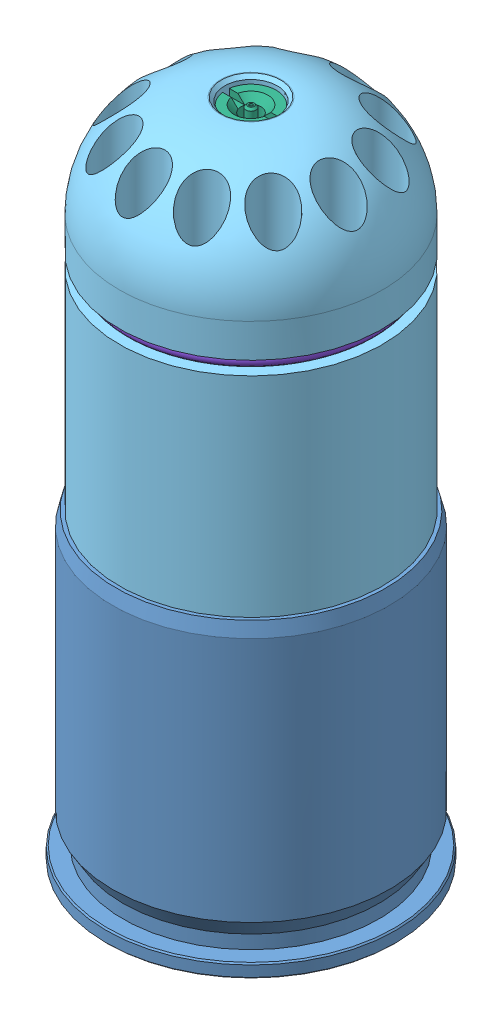
SolidWorks assembly 40mm-Klein, configuration Standard. Lengths in mm.
Overall size (51.21 98 51.21).
11 component instances, 8 part files, 20 mates.
Components (placement in the parent):
- Boden-G-1: Boden-G [Standard] at (-10.8436 -22.8172 45) size (43 45 43)
- Drücker-G-1: Drücker-G [Standard] at (-10.8436 -22.8172 45) size (14 23 14)
- value-1: value [Standard] at (-10.8436 -4.0172 45) size (20 21.5 20)
- Lock-Kugel-1: Lock-Kugel [Standard] at (-10.8436 -3.0172 55) size (4 4 4)
- Lock-Kugel-2: Lock-Kugel [Standard] at (-0.8436 -3.0172 45) size (4 4 4)
- Lock-Kugel-3: Lock-Kugel [Standard] at (-20.8436 -3.0172 45) size (4 4 4)
- Lock-Kugel-4: Lock-Kugel [Standard] at (-10.8436 -3.0172 35) size (4 4 4)
- Vorn-K-1: Vorn-K [Standard] at (-10.8436 5.6828 45) x (0.99501 0 0.099776) z (-0.099776 0 0.99501) size (39 69.5 39)
- Einfüllventil-1: Einfüllventil [Standard] at (-10.8436 61.6828 45) size (7.5 12.5 7.5)
- value-gegen-1: value-gegen [Standard] at (-10.8436 11.4828 45) x (1 0 -0.000025) z (0.000025 0 1) size (17.5 18.5 17.5)
- O-Ring oben-1: O-Ring oben [Standard] at (-10.8436 54.1828 45) x (-0.837169 0 -0.546944) z (-0.546944 0 0.837169) size (37 2 37)
Mates (geometry in assembly coordinates):
- Konzentrisch1: concentric anti-aligned: cylinder of Boden-G-1 through (-10.8436 -21.8172 45) axis (0 1 0) radius 7; cylinder of Drücker-G-1 through (-10.8436 -12.8172 45) axis (0 -1 0) radius 7
- Deckungsgleich1: coincident aligned: plane of Boden-G-1 through (-10.8436 -22.8172 45) normal (0 -1 0); plane of Drücker-G-1 through (-10.8436 -22.8172 45) normal (0 -1 0)
- Konzentrisch2: concentric: cylinder of value-1 through (-10.8436 -1.0172 35) axis (0 0 1) radius 2; sphere of Lock-Kugel-1
- Tangential2: tangent: curve of value-1; sphere of Lock-Kugel-1
- Konzentrisch3: concentric: cylinder of value-1 through (-20.8436 -1.0172 45) axis (1 0 0) radius 2; sphere of Lock-Kugel-2
- Tangential4: tangent: curve of value-1; sphere of Lock-Kugel-2
- Konzentrisch4: concentric: cylinder of value-1 through (-10.8436 -1.0172 35) axis (0 0 1) radius 2; sphere of Lock-Kugel-4
- Tangential6: tangent: curve of value-1; sphere of Lock-Kugel-4
- Konzentrisch5: concentric: cylinder of value-1 through (-20.8436 -1.0172 45) axis (1 0 0) radius 2; sphere of Lock-Kugel-3
- Tangential8: tangent: curve of value-1; sphere of Lock-Kugel-3
- Deckungsgleich2: coincident aligned: circle of Boden-G-1; cylinder of value-1 through (-10.8436 4.9828 45) axis (0 -1 0) radius 10
- Konzentrisch6: concentric anti-aligned: cylinder of Vorn-K-1 through (-10.8436 5.6828 45) axis (0 1 0) radius 2; cylinder of Einfüllventil-1 through (-10.8436 72.1828 45) axis (0 -1 0) radius 2
- Deckungsgleich3: coincident anti-aligned: plane of Vorn-K-1 through (-10.8436 72.1828 45) normal (0 1 0); plane of Einfüllventil-1 through (-10.8436 72.1828 45) normal (0 -1 0)
- Deckungsgleich4: coincident anti-aligned: plane of Vorn-K-1 through (-10.8436 13.4828 45) normal (0 -1 0); plane of value-gegen-1 through (-10.8436 13.4828 45) normal (0 1 0)
- Konzentrisch7: concentric: cylinder of Vorn-K-1 through (-10.8436 62.6828 45) axis (0 -1 0) radius 7.5; cylinder of value-gegen-1 through (-10.8436 29.9828 45) axis (0 -1 0) radius 7.5
- Deckungsgleich5: coincident anti-aligned: plane of value-1 through (-10.8436 11.4828 45) normal (0 1 0); plane of value-gegen-1 through (-10.8436 11.4828 45) normal (0 -1 0)
- Konzentrisch8: concentric aligned: cylinder of value-1 through (-10.8436 17.4828 45) axis (0 -1 0) radius 4.95; cylinder of value-gegen-1 through (-10.8436 19.2828 45) axis (0 -1 0) radius 5
- Deckungsgleich6: coincident anti-aligned: plane of Boden-G-1 through (-10.8436 22.1828 45) normal (0 1 0); plane of Vorn-K-1 through (-10.8436 22.1828 45) normal (0 -1 0)
- Tangential9: tangent: plane of Vorn-K-1 through (-32.7123 53.1828 42.8071) normal (0 1 0); torus of O-Ring oben-1
- Tangential10: tangent: cylinder of Vorn-K-1 through (-10.8436 75.1828 45) axis (0 1 0) radius 16.5; torus of O-Ring oben-1
